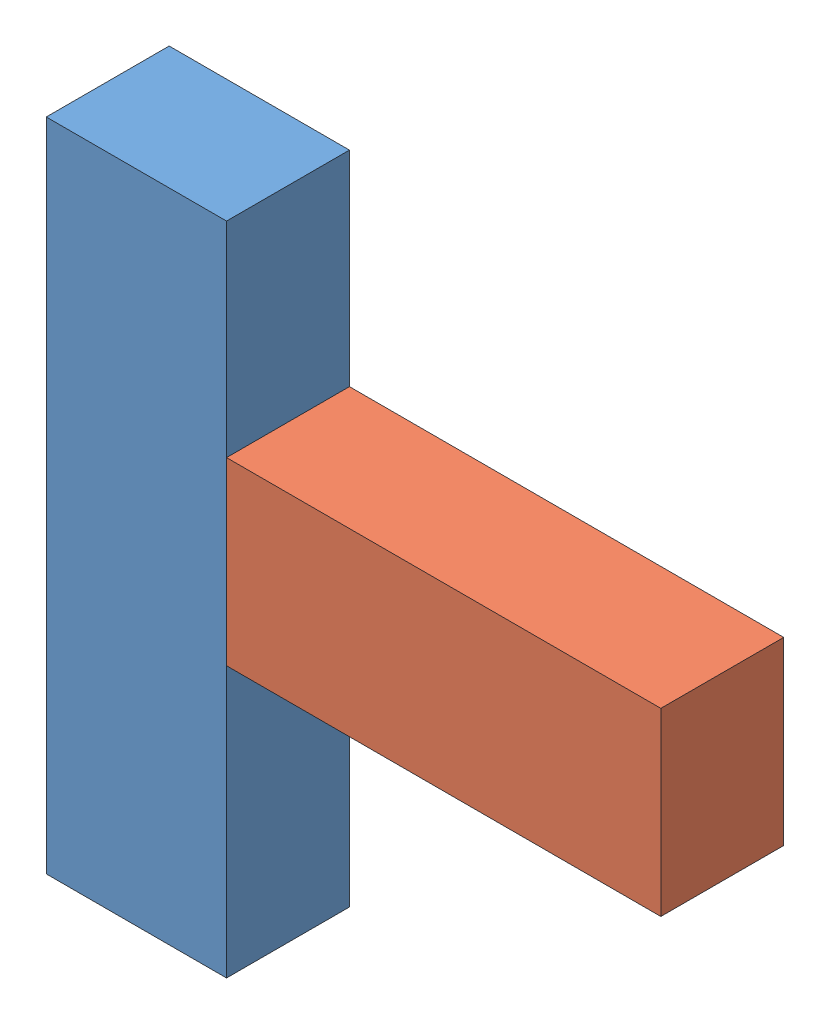
SolidWorks assembly Assem3, configuration Default. Lengths in mm.
Overall size (150 160 30).
2 component instances, 2 part files, 3 mates.
Components (placement in the parent):
- Vertical Piece-1: Vertical Piece [Default] at (83.1834 3.61 73.3333) size (44 160 30)
- Rail Piece-1: Rail Piece [Default] at (83.1834 69.61 73.3333) size (150 44 30)
Mates (geometry in assembly coordinates):
- Coincident1: coincident anti-aligned: plane of Vertical Piece-1 through (83.1824 113.61 93.3333) normal (0 0 -1); plane of Rail Piece-1 through (83.1834 69.609 93.3333) normal (0 0 1)
- Coincident2: coincident anti-aligned: plane of Vertical Piece-1 through (83.1824 113.61 93.3333) normal (0 -1 0); plane of Rail Piece-1 through (83.1834 113.61 103.3333) normal (0 1 0)
- Coincident3: coincident aligned: plane of Vertical Piece-1 through (83.1834 3.61 103.3333) normal (-1 0 0); plane of Rail Piece-1 through (83.1834 69.61 103.3333) normal (-1 0 0)
